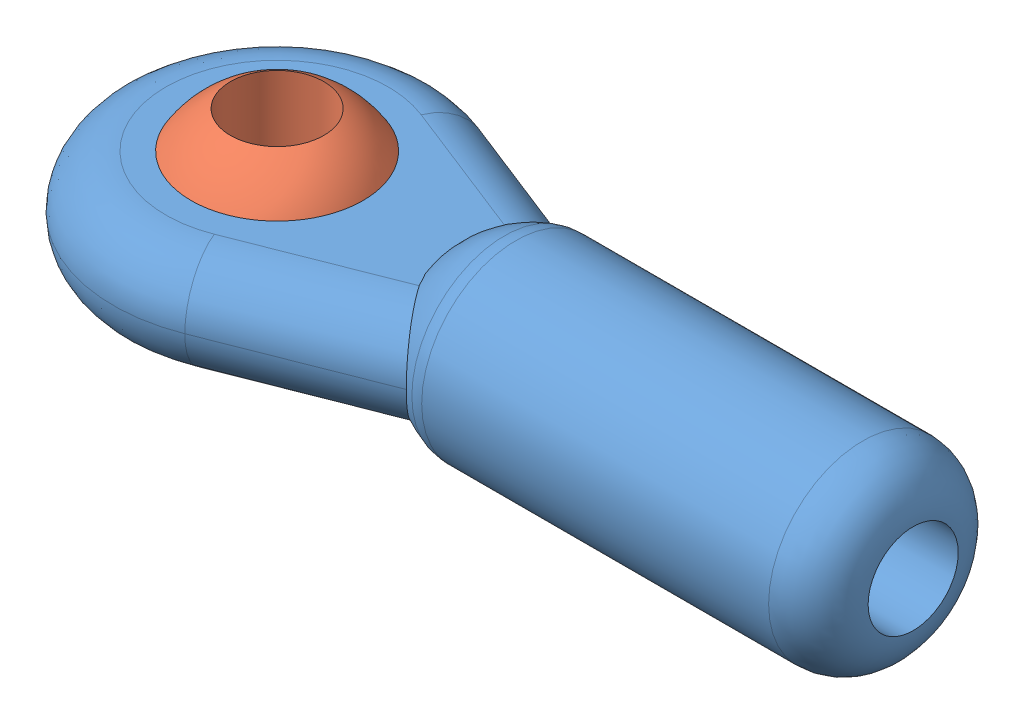
SolidWorks assembly balljoint, configuration Default. Lengths in mm.
Overall size (25.24 5.95 10.32).
2 component instances, 2 part files, 1 mates.
Components (placement in the parent):
- balljoint_joint-1: balljoint_joint [Default] at (-6.0674 0.1484 2.2064) size (25.24 5.95 10.32)
- balljoint_ball-2: balljoint_ball [Default] at (-13.4478 0.1484 2.2064) size (6.35 5.63 6.35)
Mates (geometry in assembly coordinates):
- Concentric1: concentric: sphere of balljoint_joint-1; sphere of balljoint_ball-2
